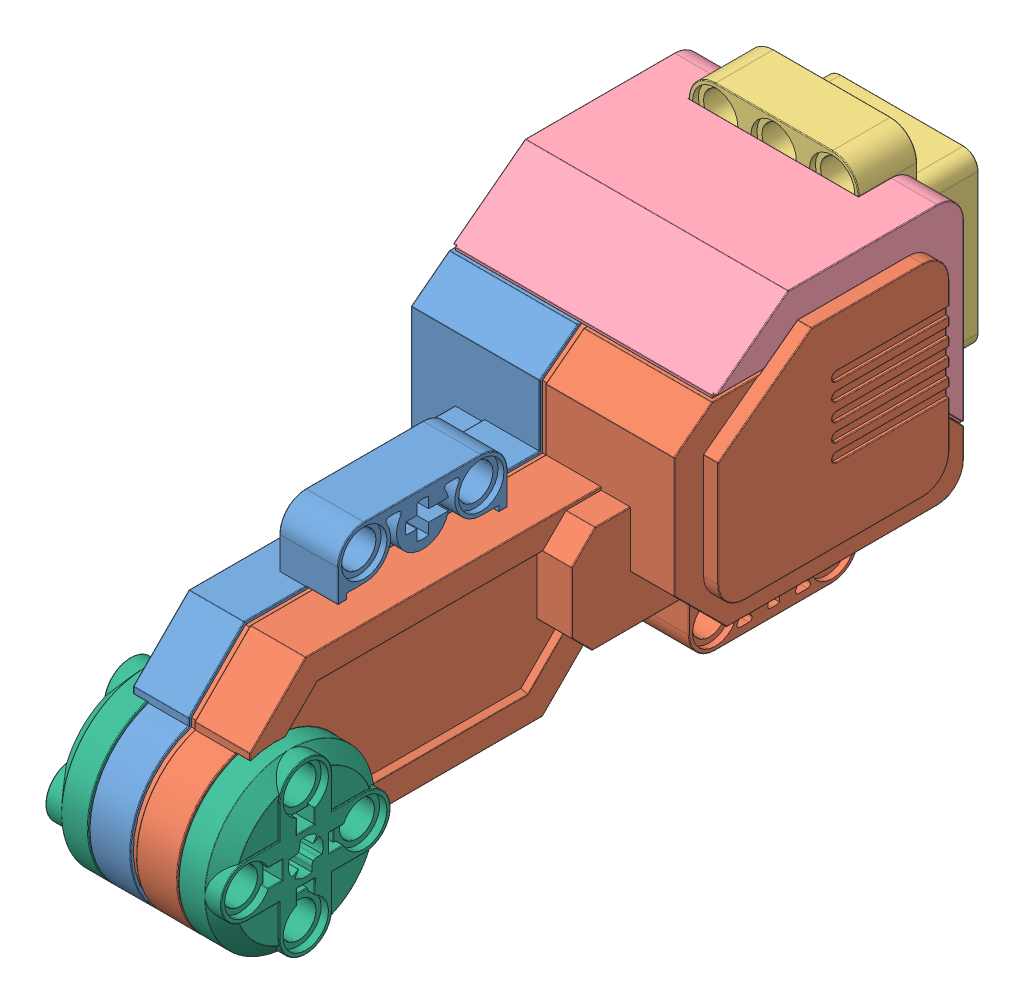
SolidWorks assembly LEGOEV3LARGEMOTOR, configuration Default. Lengths in mm.
Overall size (40 55.2 107.2).
9 component instances, 6 part files, 0 mates.
Components (placement in the parent):
- 95658.stp-1: 95658.stp [Default] at origin size (40 55.2 107.2)
  - 99550c01.stp-1: 99550c01.stp [Default] at origin size (40 55.2 107.2)
    - 99550-LtBluishGray.stp-1: 99550-LtBluishGray.stp [Default] x (-1 0 0) z (0 0 -1) size (24 47.6 95.62)
    - 99551-LtBluishGray.stp-1: 99551-LtBluishGray.stp [Default] at (0.8 0 0) x (-1 0 0) z (0 0 -1) size (20.4 47.6 95.61)
    - 10825-LtBluishGray.stp-1: 10825-LtBluishGray.stp [Default] at (0.4 24 -84) x (-1 0 0) z (0 0 -1) size (30.4 39.2 19.6)
    - 99555-White.stp-1: 99555-White.stp [Default] at (0.4 24.2 -70.2) x (-1 0 0) z (0 0 -1) size (36 27.86 34)
    - 54732b-LtBluishGray.stp-1: 54732b-LtBluishGray.stp [Default] at (0.4 23.6 -95.6) x (-1 0 0) z (0 0 -1) size (12 14.56 14.4)
  - 99617-Red.stp-1: 99617-Red.stp [Default] at (-5.8 0 0) x (-1 0 0) z (0 0 -1) size (12 23.2 23.2)
  - 99617-Red.stp-2: 99617-Red.stp [Default] at (6.6 0 0) size (12 23.2 23.2)
